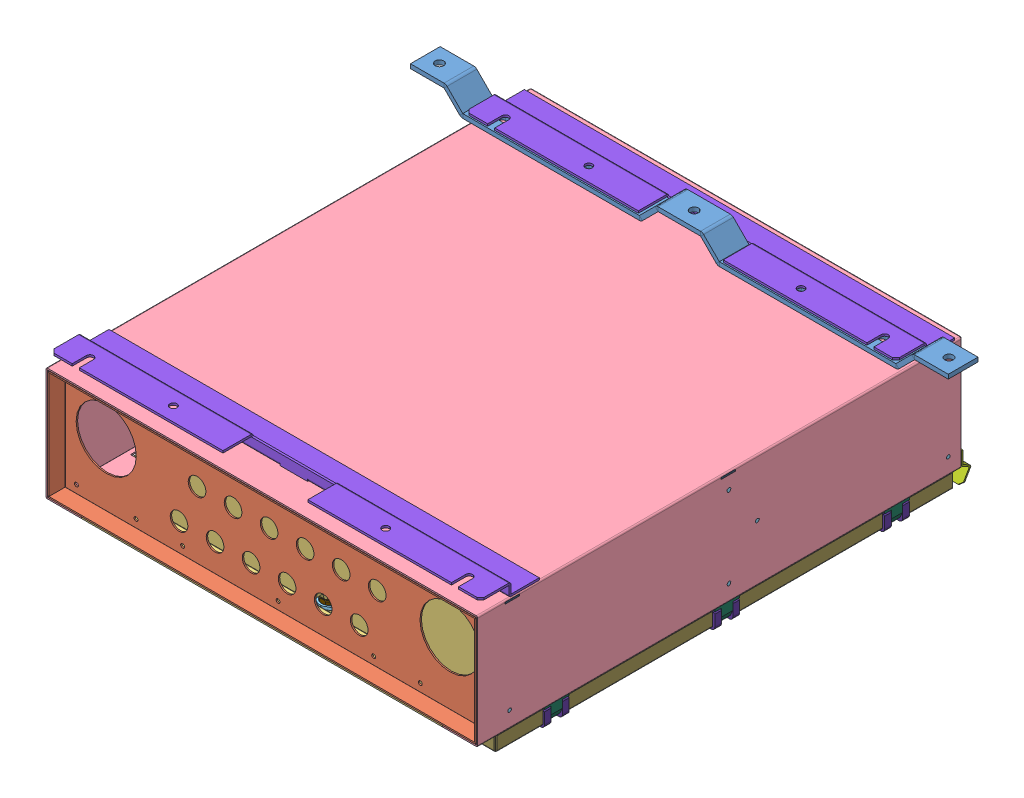
SolidWorks assembly ENCLOSURE-walmounts, configuration Défaut. Lengths in mm.
Overall size (760 258.08 763.89).
106 component instances, 24 part files, 2 mates.
Components (placement in the parent):
- WALLMOUNTS-1: WALLMOUNTS [Défaut] at (-217.1962 3.6086 0) size (760 30 42)
- Assemblage-ENCLOSURE-1: Assemblage-ENCLOSURE [Défaut] at (-224.7912 -305.7958 679.1871) x (-0.053903 0 0.998546) z (0 1 0) size (730.09 646.75 237.08)
  - Assemblage-CORPS-ENCLOSURE-1: Assemblage-CORPS-ENCLOSURE [Défaut] at (-83.9444 -173.7332 203.1798) x (0.053903 -0.998546 0) z (-0.998546 -0.053903 0) size (610 203.33 698.22)
    - ENCLOSURE-SOCLE-1: ENCLOSURE-SOCLE [Défaut] at (-176.6 -13.0254 0) size (605.5 155.51 25.01)
    - ENCLOSURE-RETOUR-SOCLE-1: ENCLOSURE-RETOUR-SOCLE [Défaut] at (-176.6 -106.7754 35) x (0 0 -1) z (1 0 0) size (60 16 532)
    - ENCLOSURE-CORPS-1: ENCLOSURE-CORPS [Défaut] at (-123.8261 65.2246 285.1261) x (1 0 0) z (0 -1 0) size (610 685 174)
      - ENCLOSURE-CORPS-1: ENCLOSURE-CORPS [Défaut] at (-52.7739 32.3739 0) size (610 685 174)
      - FHSM5X15-2: FHSM5X15 [PEM FHS-M5-15 ---N] at (252.2261 354.8739 135.2) x (-1 0 0) z (0 0.924225 0.381849) size (15 6.5 6.5)
      - FHSM5X15-3: FHSM5X15 [PEM FHS-M5-15 ---N] at (252.2261 354.8739 20.8) x (-1 0 0) z (0 0.924225 0.381849) size (15 6.5 6.5)
      - FHSM5X15-4: FHSM5X15 [PEM FHS-M5-15 ---N] at (252.2261 84.8739 78) x (-1 0 0) z (0 0.924225 0.381849) size (15 6.5 6.5)
      - FHSM5X15-5: FHSM5X15 [PEM FHS-M5-15 ---N] at (252.2261 44.8739 135.2) x (-1 0 0) z (0 0.924225 0.381849) size (15 6.5 6.5)
      - FHSM5X15-6: FHSM5X15 [PEM FHS-M5-15 ---N] at (252.2261 44.8739 20.8) x (-1 0 0) z (0 0.924225 0.381849) size (15 6.5 6.5)
      - FHSM5X15-7: FHSM5X15 [PEM FHS-M5-15 ---N] at (252.2261 314.8739 78) x (-1 0 0) z (0 0.924225 0.381849) size (15 6.5 6.5)
      - FHSM5X15-8: FHSM5X15 [PEM FHS-M5-15 ---N] at (-357.7739 354.8739 20.8) size (15 6.5 6.5)
      - FHSM5X15-9: FHSM5X15 [PEM FHS-M5-15 ---N] at (-357.7739 354.8739 135.2) size (15 6.5 6.5)
      - FHSM5X15-10: FHSM5X15 [PEM FHS-M5-15 ---N] at (-357.7739 44.8739 20.8) size (15 6.5 6.5)
      - FHSM5X15-11: FHSM5X15 [PEM FHS-M5-15 ---N] at (-357.7739 84.8739 78) size (15 6.5 6.5)
      - FHSM5X15-12: FHSM5X15 [PEM FHS-M5-15 ---N] at (-357.7739 44.8739 135.2) size (15 6.5 6.5)
      - INSERTHM6X30BIN-1: INSERTHM6X30BIN [Défaut] at (232.4261 354.8739 78) x (0 -0.866025 -0.5) z (0 -0.5 0.866025) size (13.8 19.8 13.8)
      - INSERTHM6X30BIN-2: INSERTHM6X30BIN [Défaut] at (232.4261 44.8739 78) x (0 -0.866025 -0.5) z (0 -0.5 0.866025) size (13.8 19.8 13.8)
      - INSERTHM6X30BIN-3: INSERTHM6X30BIN [Défaut] at (232.4261 314.8739 135.2) x (0 -0.866025 -0.5) z (0 -0.5 0.866025) size (13.8 19.8 13.8)
      - INSERTHM6X30BIN-4: INSERTHM6X30BIN [Défaut] at (232.4261 314.8739 20.8) x (0 -0.866025 -0.5) z (0 -0.5 0.866025) size (13.8 19.8 13.8)
      - INSERTHM6X30BIN-5: INSERTHM6X30BIN [Défaut] at (232.4261 84.8739 135.2) x (0 -0.866025 -0.5) z (0 -0.5 0.866025) size (13.8 19.8 13.8)
      - INSERTHM6X30BIN-6: INSERTHM6X30BIN [Défaut] at (232.4261 84.8739 20.8) x (0 -0.866025 -0.5) z (0 -0.5 0.866025) size (13.8 19.8 13.8)
      - FHSM5X15-13: FHSM5X15 [PEM FHS-M5-15 ---N] at (252.2261 -265.1261 135.2) x (-1 0 0) z (0 0.924225 0.381849) size (15 6.5 6.5)
      - FHSM5X15-14: FHSM5X15 [PEM FHS-M5-15 ---N] at (-357.7739 -265.1261 135.2) size (15 6.5 6.5)
    - ENCLOSURE-CASQUETTE-1: ENCLOSURE-CASQUETTE [Défaut] at (-176.6 -72.9878 660) x (0 -1 0) z (-1 0 0) size (45.12 13.22 607)
    - ENCLOSURE-BARRE-MONTAGE-1: ENCLOSURE-BARRE-MONTAGE [Défaut] at (-176.6 70.2246 650) x (0 1 0) z (1 0 0) size (18 83 608)
    - ENCLOSURE-BARRE-MONTAGE-2: ENCLOSURE-BARRE-MONTAGE [Défaut] at (-176.6 70.2246 63) x (0 1 0) z (1 0 0) size (18 83 608)
    - Assemblage-ENCLOSURE-OMEGA-CORPS-1: Assemblage-ENCLOSURE-OMEGA-CORPS [Défaut] at (-425.3614 51.4326 48.965) x (-1 0 0) z (0 0 1) size (101 20 630)
      - INSERTHM6X30IN-1: INSERTHM6X30IN [Défaut] at (-7.7614 5.808 0) size (10 12.4 10.93)
      - ENCLOSURE-OMEGA-CORPS-1: ENCLOSURE-OMEGA-CORPS [Défaut] at (-7.7614 15.208 -4.93) size (101 20 630)
      - INSERTHM6X30IN-2: INSERTHM6X30IN [Défaut] at (-7.7614 5.808 80.01) size (10 12.4 10.93)
      - INSERTHM6X30IN-3: INSERTHM6X30IN [Défaut] at (-7.7614 5.808 160.02) size (10 12.4 10.93)
      - INSERTHM6X30IN-4: INSERTHM6X30IN [Défaut] at (-7.7614 5.808 240.03) size (10 12.4 10.93)
      - INSERTHM6X30IN-5: INSERTHM6X30IN [Défaut] at (-7.7614 5.808 320.04) size (10 12.4 10.93)
      - INSERTHM6X30IN-6: INSERTHM6X30IN [Défaut] at (-7.7614 5.808 400.05) size (10 12.4 10.93)
      - INSERTHM6X30IN-7: INSERTHM6X30IN [Défaut] at (-7.7614 5.808 480.06) size (10 12.4 10.93)
      - INSERTHM6X30IN-8: INSERTHM6X30IN [Défaut] at (-7.7614 5.808 560.07) size (10 12.4 10.93)
    - Assemblage-ENCLOSURE-OMEGA-CORPS-9: Assemblage-ENCLOSURE-OMEGA-CORPS [Défaut] at (72.1614 51.4326 609.035) x (1 0 0) z (0 0 -1) size (101 20 630)
      - INSERTHM6X30IN-1: INSERTHM6X30IN [Défaut] at (-7.7614 5.808 0) size (10 12.4 10.93)
      - ENCLOSURE-OMEGA-CORPS-1: ENCLOSURE-OMEGA-CORPS [Défaut] at (-7.7614 15.208 -4.93) size (101 20 630)
      - INSERTHM6X30IN-2: INSERTHM6X30IN [Défaut] at (-7.7614 5.808 80.01) size (10 12.4 10.93)
      - INSERTHM6X30IN-3: INSERTHM6X30IN [Défaut] at (-7.7614 5.808 160.02) size (10 12.4 10.93)
      - INSERTHM6X30IN-4: INSERTHM6X30IN [Défaut] at (-7.7614 5.808 240.03) size (10 12.4 10.93)
      - INSERTHM6X30IN-5: INSERTHM6X30IN [Défaut] at (-7.7614 5.808 320.04) size (10 12.4 10.93)
      - INSERTHM6X30IN-6: INSERTHM6X30IN [Défaut] at (-7.7614 5.808 400.05) size (10 12.4 10.93)
      - INSERTHM6X30IN-7: INSERTHM6X30IN [Défaut] at (-7.7614 5.808 480.06) size (10 12.4 10.93)
      - INSERTHM6X30IN-8: INSERTHM6X30IN [Défaut] at (-7.7614 5.808 560.07) size (10 12.4 10.93)
    - 31807008201-1: 31807008201 [Défaut] at (-438.1 -103.7754 330) x (0 1 0) z (0 0 1) size (17 19 603)
  - AssemblagePORTE-1: AssemblagePORTE [Défaut] at (-329.5147 -57.1633 87.4044) x (0.998546 0.053903 0) z (0 0 1) size (648 602 66.85)
    - Assemblage-PORTE-OMEGA-1: Assemblage-PORTE-OMEGA [Défaut] at (-31.9244 22.5518 0) size (648 599 22)
      - ENCLOSURE-PORTE-1: ENCLOSURE-PORTE [Défaut] at (-58.8958 24.4108 0) size (648 599 20)
      - Assemblage-ENCLOSURE-OMEGA-1: Assemblage-ENCLOSURE-OMEGA [Défaut] at (-30.8854 309.3758 10.704) x (1 0 0) z (0 -1 0) size (74 20 450)
        - ENCLOSURE-OMEGA-PORTE-1: ENCLOSURE-OMEGA-PORTE [Défaut] at (-28.0104 18.296 0) size (74 20 450)
        - INSERTHM6X30IN-1: INSERTHM6X30IN [Défaut] at (-28.0104 8.896 484.99) size (10 12.4 10.93)
        - INSERTHM6X30IN-2: INSERTHM6X30IN [Défaut] at (-28.0104 8.896 404.98) size (10 12.4 10.93)
        - INSERTHM6X30IN-3: INSERTHM6X30IN [Défaut] at (-28.0104 8.896 324.97) size (10 12.4 10.93)
        - INSERTHM6X30IN-4: INSERTHM6X30IN [Défaut] at (-28.0104 8.896 244.96) size (10 12.4 10.93)
        - INSERTHM6X30IN-5: INSERTHM6X30IN [Défaut] at (-28.0104 8.896 164.95) size (10 12.4 10.93)
        - INSERTHM6X30IN-6: INSERTHM6X30IN [Défaut] at (-28.0104 8.896 84.94) size (10 12.4 10.93)
      - EQUERRE2.5PORTE-1: EQUERRE2.5PORTE [Défaut] at (-58.8958 309.7908 2.5) x (0 1 0) z (0 0 1) size (23.7 640 17.86)
    - CH04568150PCL-1: CH04568150PCL [Défaut] at (-91.0702 350.6665 7.0562) x (0 1 0) z (1 0 0) size (21 29.5 62)
      - CH04568150PCLP1-1: CH04568150PCLP1 [Défaut] at (-11.2039 17.4438 0) size (20 26.85 35)
      - CH04568150PCLP3-1: CH04568150PCLP3 [Défaut] at (-12.9368 17.2115 -0.8805) x (0.996722 0.080906 0) z (0 0 1) size (14 6.01 62)
      - CH04568150PCLP2-1: CH04568150PCLP2 [Défaut] at (-11.2039 17.4438 0) size (21 23 35)
    - CH04568150PCL-3: CH04568150PCL [Défaut] at (-331.0702 350.6665 7.0562) x (0 1 0) z (1 0 0) size (21 29.5 62)
      - CH04568150PCLP1-1: CH04568150PCLP1 [Défaut] at (-11.2039 17.4438 0) size (20 26.85 35)
      - CH04568150PCLP3-1: CH04568150PCLP3 [Défaut] at (-12.9368 17.2115 -0.8805) x (0.996722 0.080906 0) z (0 0 1) size (14 6.01 62)
      - CH04568150PCLP2-1: CH04568150PCLP2 [Défaut] at (-11.2039 17.4438 0) size (21 23 35)
    - AssemblageVERROU316L-1: AssemblageVERROU316L [Défaut] at (168.1798 51.8662 4.8695) x (0 1 0) z (-1 0 0) size (28 37.77 61.63)
      - CO02960130PCL-1: CO02960130PCL [Défaut] at (-4.9037 7.8695 0) size (28 22 28)
      - JOINTVERROU-IP65-1: JOINTVERROU-IP65 [Défaut] at (-4.9037 6.8695 0) x (1 0 0) z (0 1 0) size (27.5 27.5 1)
      - RO02411250CPL-1: RO02411250CPL [Défaut] at (-4.9037 3.4695 0) x (0 1 0) z (-0.064039 0 0.997947) size (25.3 16 16)
      - CA02405480PCcame28-1: CA02405480PCcame28 [Défaut] at (-4.7975 -14.1305 -0.0934) x (0.064039 0 -0.997947) z (0.997947 0 0.064039) size (54.43 17.77 19.1)
      - VISVERROUM6-1: VISVERROUM6 [Défaut] at (-4.9037 -20.1305 0) x (1 0 0) z (0 -1 0) size (13.5 13.5 13.31)
      - ECROUVEROU-1: ECROUVEROU [Défaut] at (-4.9037 0.8695 0) x (1 0 0) z (0 1 0) size (27 31.18 4)
    - AssemblageVERROU316L-2: AssemblageVERROU316L [Défaut] at (-349.8202 42.0589 4.8695) x (0 -1 0) z (1 0 0) size (28 37.77 61.63)
      - CO02960130PCL-1: CO02960130PCL [Défaut] at (-4.9037 7.8695 0) size (28 22 28)
      - JOINTVERROU-IP65-1: JOINTVERROU-IP65 [Défaut] at (-4.9037 6.8695 0) x (1 0 0) z (0 1 0) size (27.5 27.5 1)
      - RO02411250CPL-1: RO02411250CPL [Défaut] at (-4.9037 3.4695 0) x (0 1 0) z (-0.064039 0 0.997947) size (25.3 16 16)
      - CA02405480PCcame28-1: CA02405480PCcame28 [Défaut] at (-4.7975 -14.1305 -0.0934) x (0.064039 0 -0.997947) z (0.997947 0 0.064039) size (54.43 17.77 19.1)
      - VISVERROUM6-1: VISVERROUM6 [Défaut] at (-4.9037 -20.1305 0) x (1 0 0) z (0 -1 0) size (13.5 13.5 13.31)
      - ECROUVEROU-1: ECROUVEROU [Défaut] at (-4.9037 0.8695 0) x (1 0 0) z (0 1 0) size (27 31.18 4)
    - AssemblageVERROU316L-3: AssemblageVERROU316L [Défaut] at (54.0835 -170.5374 4.8695) x (1 0 0) z (0 1 0) size (28 37.77 61.63)
      - CO02960130PCL-1: CO02960130PCL [Défaut] at (-4.9037 7.8695 0) size (28 22 28)
      - JOINTVERROU-IP65-1: JOINTVERROU-IP65 [Défaut] at (-4.9037 6.8695 0) x (1 0 0) z (0 1 0) size (27.5 27.5 1)
      - RO02411250CPL-1: RO02411250CPL [Défaut] at (-4.9037 3.4695 0) x (0 1 0) z (-0.064039 0 0.997947) size (25.3 16 16)
      - CA02405480PCcame28-1: CA02405480PCcame28 [Défaut] at (-4.7975 -14.1305 -0.0934) x (0.064039 0 -0.997947) z (0.997947 0 0.064039) size (54.43 17.77 19.1)
      - VISVERROUM6-1: VISVERROUM6 [Défaut] at (-4.9037 -20.1305 0) x (1 0 0) z (0 -1 0) size (13.5 13.5 13.31)
      - ECROUVEROU-1: ECROUVEROU [Défaut] at (-4.9037 0.8695 0) x (1 0 0) z (0 1 0) size (27 31.18 4)
    - AssemblageVERROU316L-4: AssemblageVERROU316L [Défaut] at (-225.2642 -169.9174 4.8695) x (1 0 0) z (0 1 0) size (28 37.77 61.63)
      - CO02960130PCL-1: CO02960130PCL [Défaut] at (-4.9037 7.8695 0) size (28 22 28)
      - JOINTVERROU-IP65-1: JOINTVERROU-IP65 [Défaut] at (-4.9037 6.8695 0) x (1 0 0) z (0 1 0) size (27.5 27.5 1)
      - RO02411250CPL-1: RO02411250CPL [Défaut] at (-4.9037 3.4695 0) x (0 1 0) z (-0.064039 0 0.997947) size (25.3 16 16)
      - CA02405480PCcame28-1: CA02405480PCcame28 [Défaut] at (-4.7975 -14.1305 -0.0934) x (0.064039 0 -0.997947) z (0.997947 0 0.064039) size (54.43 17.77 19.1)
      - VISVERROUM6-1: VISVERROUM6 [Défaut] at (-4.9037 -20.1305 0) x (1 0 0) z (0 -1 0) size (13.5 13.5 13.31)
      - ECROUVEROU-1: ECROUVEROU [Défaut] at (-4.9037 0.8695 0) x (1 0 0) z (0 1 0) size (27 31.18 4)
    - AC04506760PA-1: AC04506760PA [Défaut] at (-349.8202 46.9626 -3) x (0 1 0) z (0 0 1) size (34 38.18 34.08)
    - AC04506760PA-2: AC04506760PA [Défaut] at (168.1798 46.9626 -3) x (0 1 0) z (0 0 1) size (34 38.18 34.08)
    - AC04506760PA-3: AC04506760PA [Défaut] at (-230.1678 -169.9174 -3) x (0 1 0) z (0 0 1) size (34 38.18 34.08)
    - AC04506760PA-4: AC04506760PA [Défaut] at (49.1798 -170.5374 -3) x (0 1 0) z (0 0 1) size (34 38.18 34.08)
    - CH04568150PCL-7: CH04568150PCL [Défaut] at (148.9298 349.9165 7.0562) x (0 1 0) z (1 0 0) size (21 29.5 62)
      - CH04568150PCLP1-1: CH04568150PCLP1 [Défaut] at (-11.2039 17.4438 0) size (20 26.85 35)
      - CH04568150PCLP3-1: CH04568150PCLP3 [Défaut] at (-12.9368 17.2115 -0.8805) x (0.996722 0.080906 0) z (0 0 1) size (14 6.01 62)
      - CH04568150PCLP2-1: CH04568150PCLP2 [Défaut] at (-11.2039 17.4438 0) size (21 23 35)
Mates (geometry in assembly coordinates):
- Coïncidente4: coincident anti-aligned: plane of WALLMOUNTS-1 through (-523.1962 -20.3914 21) normal (0 1 0); plane of Assemblage-ENCLOSURE-1/Assemblage-CORPS-ENCLOSURE-1/ENCLOSURE-BARRE-MONTAGE-1 through (-521.147 -20.3914 -24) normal (0 -1 0)
- Coïncidente5: coincident anti-aligned: plane of WALLMOUNTS-1 through (-269.4243 -24.6048 -21) normal (0 0 -1); plane of Assemblage-ENCLOSURE-1/Assemblage-CORPS-ENCLOSURE-1/ENCLOSURE-BARRE-MONTAGE-1 through (-521.147 -32.3914 -21) normal (0 0 1)
